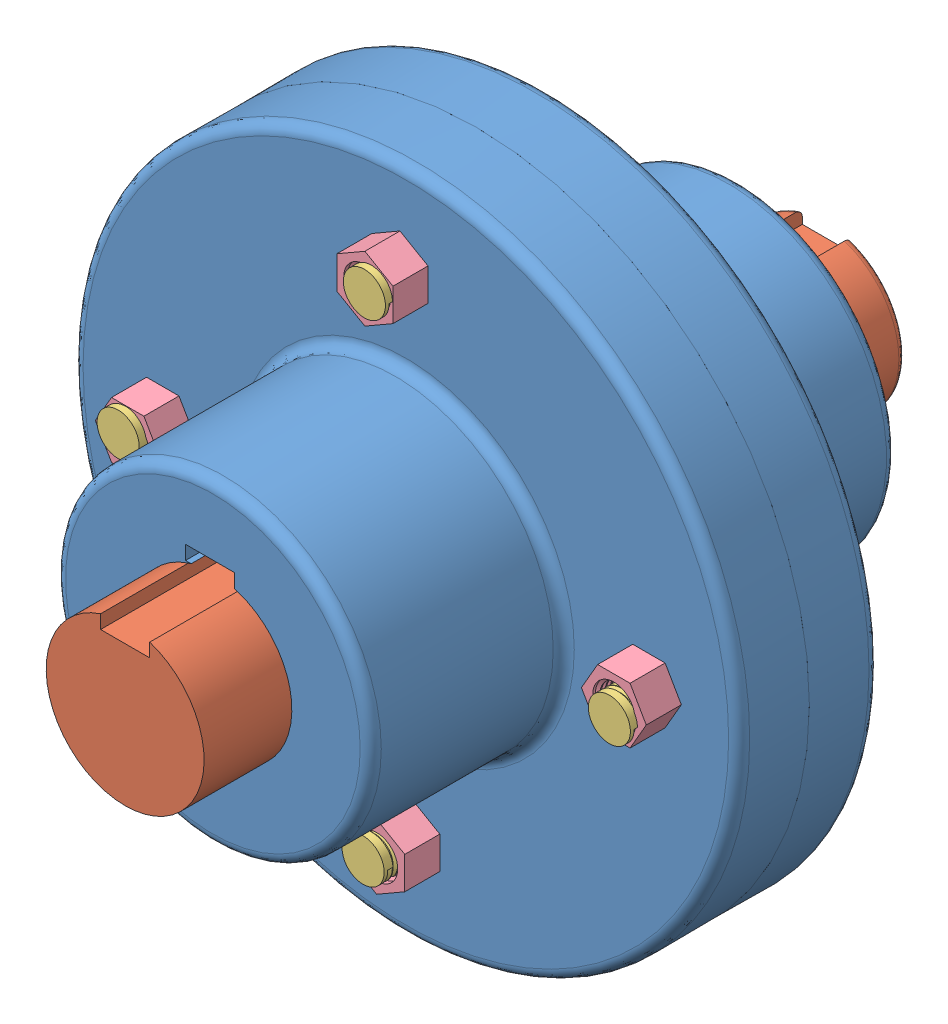
SolidWorks assembly Assembly 2 minor, configuration Default. Lengths in mm.
Overall size (190.49 190.49 200.13).
12 component instances, 4 part files, 14 mates.
Components (placement in the parent):
- minor 2.0-1: minor 2.0 [Default] at (81.1503 72.8134 120.8382) size (190 190 75)
- minor 2.0-2: minor 2.0 [Default] at (81.1503 72.8134 120.8382) x (-0.999997 0.002605 0) z (0 0 -1) size (190 190 75)
- minor 2.1-1: minor 2.1 [Default] at (81.1503 72.8134 120.8382) size (45 44.01 100.13)
- minor 2.1-2: minor 2.1 [Default] at (81.1503 72.8134 20.8382) size (45 44.01 100.13)
- minor 2.3-1: minor 2.3 [Default] at (81.3326 142.8132 152.8382) x (0.999997 -0.002605 0) z (0 0 -1) size (18.48 16 60)
- minor 2.3-2: minor 2.3 [Default] at (11.1506 72.9958 152.8382) x (0.770245 -0.637749 0) z (0 0 -1) size (18.48 16 60)
- minor 2.3-4: minor 2.3 [Default] at (80.968 2.8137 152.8382) x (1 0 0) z (0 0 -1) size (18.48 16 60)
- minor 2.3-5: minor 2.3 [Default] at (151.1501 72.6311 152.8382) x (1 0 0) z (0 0 -1) size (18.48 16 60)
- minor 2.4-1: minor 2.4 [Default] at (11.8767 71.1307 140.8382) size (18.48 16 10.57)
- minor 2.4-2: minor 2.4 [Default] at (82.833 3.5399 140.8382) x (0 1 0) z (0 0 1) size (18.48 16 10.57)
- minor 2.4-3: minor 2.4 [Default] at (150.4239 74.4962 140.8382) x (-1 0 0) z (0 0 1) size (18.48 16 10.57)
- minor 2.4-4: minor 2.4 [Default] at (79.4676 142.087 140.8382) x (0 -1 0) z (0 0 1) size (18.48 16 10.57)
Mates (geometry in assembly coordinates):
- Concentric1: concentric anti-aligned: cylinder of minor 2.0-1 through (81.1503 72.8134 259.4778) axis (0 0 -1) radius 22.5; cylinder of minor 2.0-2 through (81.1503 72.8134 -17.8015) axis (0 0 1) radius 22.5
- Concentric2: concentric aligned: cylinder of minor 2.0-1 through (81.1503 72.8134 259.4778) axis (0 0 -1) radius 22.5; cylinder of minor 2.1-1 through (81.1503 72.8134 220.8382) axis (0 0 -1) radius 22.5
- Coincident6: coincident aligned: plane of minor 2.0-1 through (81.1503 72.8134 120.8382) normal (0 0 -1); plane of minor 2.1-1 through (81.1503 72.8134 120.8382) normal (0 0 -1)
- Concentric3: concentric anti-aligned: cylinder of minor 2.0-2 through (81.1503 72.8134 -17.8015) axis (0 0 1) radius 22.5; cylinder of minor 2.1-2 through (81.1503 72.8134 120.8382) axis (0 0 -1) radius 22.5
- Coincident8: coincident aligned: plane of minor 2.0-2 through (81.1503 72.8134 120.8382) normal (0 0 1); plane of minor 2.1-2 through (81.1503 72.8134 120.8382) normal (0 0 1)
- Concentric6: concentric aligned: cylinder of minor 2.0-2 through (81.3326 142.8132 83.8676) axis (0 0 1) radius 6; cylinder of minor 2.3-1 through (81.3326 142.8132 100.8382) axis (0 0 1) radius 6
- Coincident9: coincident anti-aligned: plane of minor 2.0-2 through (81.1503 72.8134 100.8382) normal (0 0 -1); plane of minor 2.3-1 through (81.3326 142.8132 100.8382) normal (0 0 1)
- Concentric9: concentric aligned: cylinder of minor 2.0-2 through (11.1506 72.9958 83.8676) axis (0 0 1) radius 6; cylinder of minor 2.3-2 through (11.1506 72.9958 100.8382) axis (0 0 1) radius 6
- Coincident12: coincident anti-aligned: plane of minor 2.0-2 through (81.1503 72.8134 100.8382) normal (0 0 -1); plane of minor 2.3-2 through (11.1506 72.9958 100.8382) normal (0 0 1)
- Concentric11: concentric aligned: cylinder of minor 2.0-2 through (80.968 2.8137 83.8676) axis (0 0 1) radius 6; cylinder of minor 2.3-4 through (80.968 2.8137 100.8382) axis (0 0 1) radius 6
- Coincident13: coincident anti-aligned: plane of minor 2.0-2 through (81.1503 72.8134 100.8382) normal (0 0 -1); plane of minor 2.3-4 through (80.968 2.8137 100.8382) normal (0 0 1)
- Concentric12: concentric aligned: cylinder of minor 2.0-2 through (151.1501 72.6311 83.8676) axis (0 0 1) radius 6; cylinder of minor 2.3-5 through (151.1501 72.6311 100.8382) axis (0 0 1) radius 6
- Coincident14: coincident anti-aligned: plane of minor 2.0-2 through (81.1503 72.8134 100.8382) normal (0 0 -1); plane of minor 2.3-5 through (151.1501 72.6311 100.8382) normal (0 0 1)
- Coincident20: coincident anti-aligned: plane of minor 2.0-1 through (81.1503 72.8134 140.8382) normal (0 0 1); plane of minor 2.4-1 through (11.8767 71.1307 140.8382) normal (0 0 -1)
